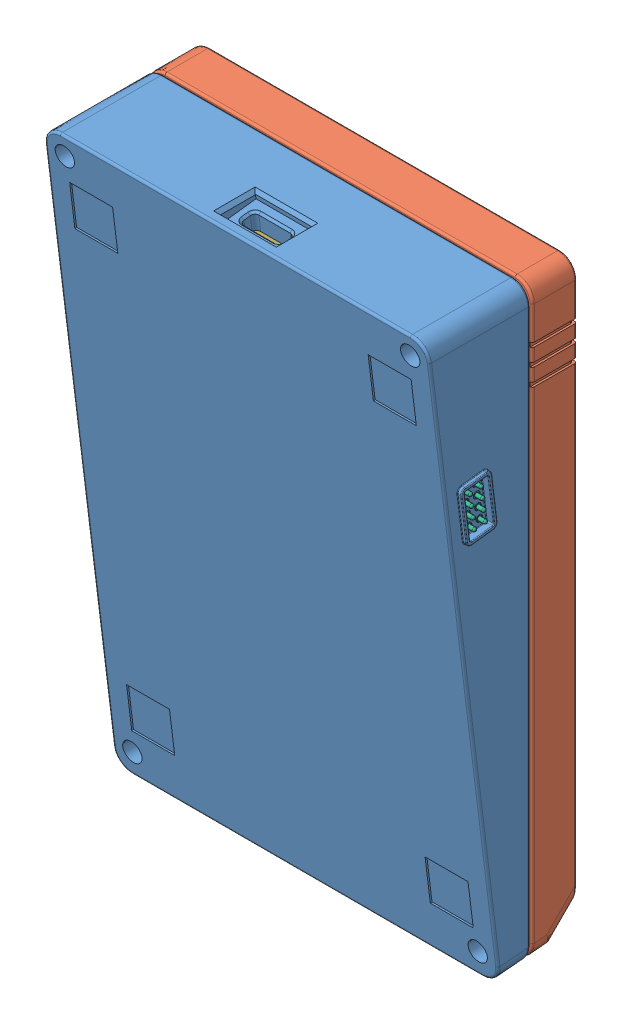
SolidWorks assembly 00-装配体 数字键盘, configuration 默认. Lengths in mm.
Overall size (91.3 137.62 34.75).
6 component instances, 6 part files, 15 mates.
Components (placement in the parent):
- 02-零件 数字键盘底壳-1: 02-零件 数字键盘底壳 [默认] at (-38.8562 -68.9403 127.6405) size (91.2 137.62 26.75)
- 01 零件 数字键盘上盖-1: 01 零件 数字键盘上盖 [默认] at (50.6438 -70.6968 127.6405) x (-1 0 0) z (0 0 -1) size (89.5 136.95 11.4)
- 04-零件 数字键盘PCB板-1: 04-零件 数字键盘PCB板 [默认] at (-4.0566 -38.8699 127.6405) size (76.5 124.09 1.2)
- 03-零件 数字键盘定位板-1: 03-零件 数字键盘定位板 [默认] at (-23.3554 -59.5126 122.6405) x (1 0 0) z (0 -1 0) size (83.5 1.6 131.09)
- 08-Q零件 顶针2x4pin 母座-1: 08-Q零件 顶针2x4pin 母座 [默认] at (-37.2562 32.9757 142.9374) x (0 -0.992546 -0.121869) z (0 -0.121869 0.992546) size (10.2 6.8 5)
- 09-Q零件 顶针2x4pin 公头-1: 09-Q零件 顶针2x4pin 公头 [默认] at (48.9438 22.8518 141.6943) x (0 0.992546 0.121869) z (0 -0.121869 0.992546) size (10.2 6.85 5)
Mates (geometry in assembly coordinates):
- 重合4: coincident anti-aligned: plane of 02-零件 数字键盘底壳-1 through (-38.8562 -68.9403 127.6405) normal (0 0 -1); plane of 01 零件 数字键盘上盖-1 through (-38.8562 -70.6968 127.6405) normal (0 0 1)
- 重合5: coincident: line of 02-零件 数字键盘底壳-1 through (46.6438 66.3032 127.6405) axis (-1 0 0); plane of 01 零件 数字键盘上盖-1 through (-38.8562 66.3032 127.6405) normal (0 1 0)
- 重合6: coincident: line of 02-零件 数字键盘底壳-1 through (-38.8562 62.3032 127.6405) axis (0 -1 0); plane of 01 零件 数字键盘上盖-1 through (-38.8562 -70.6968 127.6405) normal (-1 0 0)
- 重合10: coincident anti-aligned: plane of 02-零件 数字键盘底壳-1 through (-34.7062 58.5032 124.2405) normal (0 0 -1); plane of 03-零件 数字键盘定位板-1 through (-34.7062 58.5032 124.2405) normal (0 0 1)
- 重合11: coincident anti-aligned: line of 02-零件 数字键盘底壳-1 through (-35.8562 -62.9843 124.2405) axis (0 1 0); line of 03-零件 数字键盘定位板-1 through (-35.8562 58.5032 124.2405) axis (0 -1 0)
- 重合13: coincident anti-aligned: line of 02-零件 数字键盘底壳-1 through (42.8438 -67.7843 124.2405) axis (-1 0 0); line of 03-零件 数字键盘定位板-1 through (-31.0562 -67.7843 124.2405) axis (1 0 0)
- 重合14: coincident anti-aligned: plane of 02-零件 数字键盘底壳-1 through (-38.8562 -68.9403 128.8405) normal (0 0 -1); plane of 04-零件 数字键盘PCB板-1 through (-4.0566 -38.8699 128.8405) normal (0 0 1)
- 距离1: distance = 0.5 mm anti-aligned: plane of 04-零件 数字键盘PCB板-1 through (-32.3562 -64.2843 128.8405) normal (0 -1 0); plane of 02-零件 数字键盘底壳-1 through (-38.8562 -64.7843 288.1411) normal (0 1 0)
- 距离2: distance = 0.5 mm anti-aligned: plane of 04-零件 数字键盘PCB板-1 through (-32.3562 59.8032 128.8405) normal (-1 0 0); plane of 02-零件 数字键盘底壳-1 through (-32.8562 -68.9403 288.1411) normal (1 0 0)
- 重合17: coincident anti-aligned: plane of 02-零件 数字键盘底壳-1 through (-37.2562 -68.9403 127.6405) normal (1 0 0); plane of 08-Q零件 顶针2x4pin 母座-1 through (-37.2562 32.9757 142.9374) normal (-1 0 0)
- 同心1: concentric aligned: circle of 02-零件 数字键盘底壳-1; circle of 08-Q零件 顶针2x4pin 母座-1
- 同心2: concentric aligned: cylinder of 02-零件 数字键盘底壳-1 through (-39.6562 24.2821 140.6307) axis (1 0 0) radius 0.725; circle of 08-Q零件 顶针2x4pin 母座-1
- 重合18: coincident anti-aligned: plane of 02-零件 数字键盘底壳-1 through (48.9438 -68.9403 127.6405) normal (-1 0 0); plane of 09-Q零件 顶针2x4pin 公头-1 through (48.9438 22.8518 141.6943) normal (1 0 0)
- 同心3: concentric aligned: circle of 02-零件 数字键盘底壳-1; circle of 09-Q零件 顶针2x4pin 公头-1
- 同心4: concentric aligned: circle of 02-零件 数字键盘底壳-1; circle of 09-Q零件 顶针2x4pin 公头-1
